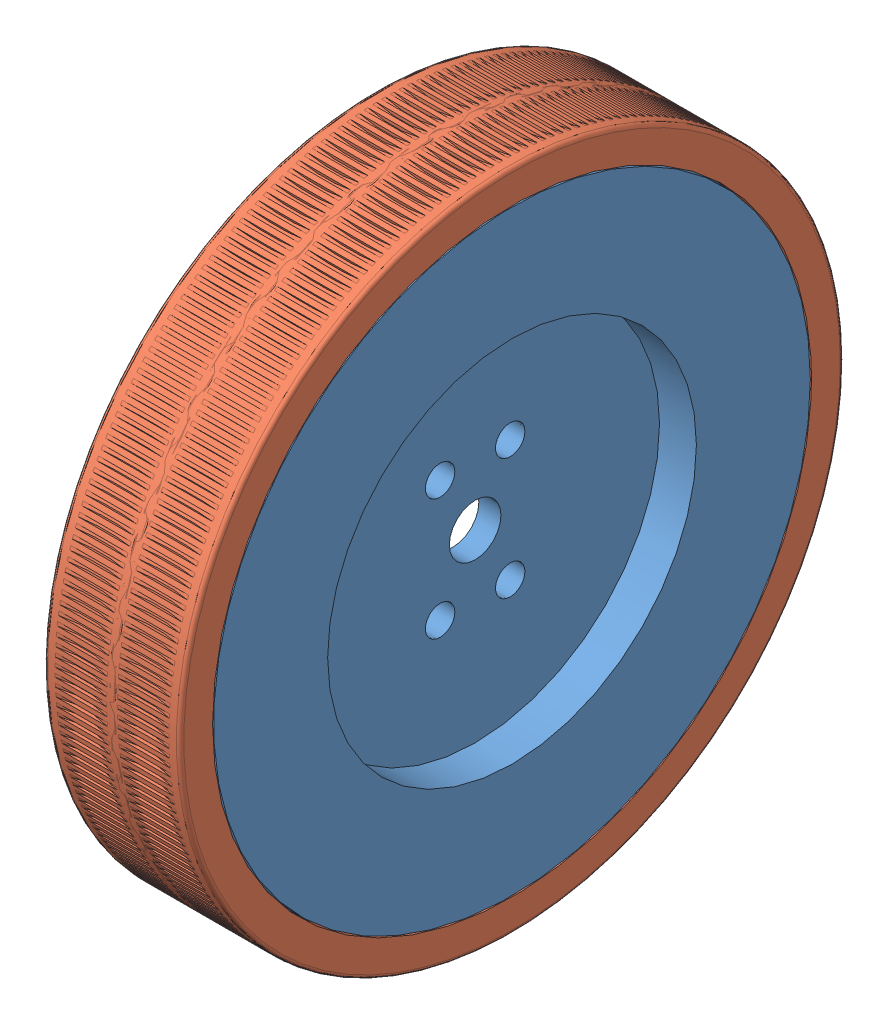
SolidWorks assembly 3ajla, configuration Default. Lengths in mm.
Overall size (20 91.33 91.33).
3 component instances, 2 part files, 4 mates.
Components (placement in the parent):
- Tombour-1: Tombour [Défaut] at (26.609 38.7622 75.4412) size (20 87 87)
- cwatchou 3ajla pululu-1: cwatchou 3ajla pululu [Default] at (24.609 38.7622 75.4412) x (0 0 -1) z (1 0 0) size (90 90 10)
- cwatchou 3ajla pululu-2: cwatchou 3ajla pululu [Default] at (16.159 38.7622 75.4412) x (0 0.014895 0.999889) z (1 0 0) size (90 90 10)
Mates (geometry in assembly coordinates):
- Concentric1: concentric: circle of Tombour-1; circle of cwatchou 3ajla pululu-1
- Concentric2: concentric: circle of Tombour-1; circle of cwatchou 3ajla pululu-2
- Coincident1: coincident aligned: plane of Tombour-1 through (16.159 38.7622 75.4412) normal (-1 0 0); plane of cwatchou 3ajla pululu-2 through (16.159 38.7622 75.4412) normal (-1 0 0)
- Coincident2: coincident aligned: plane of Tombour-1 through (34.609 78.7622 75.4412) normal (1 0 0); plane of cwatchou 3ajla pululu-1 through (34.609 38.7622 75.4412) normal (1 0 0)
